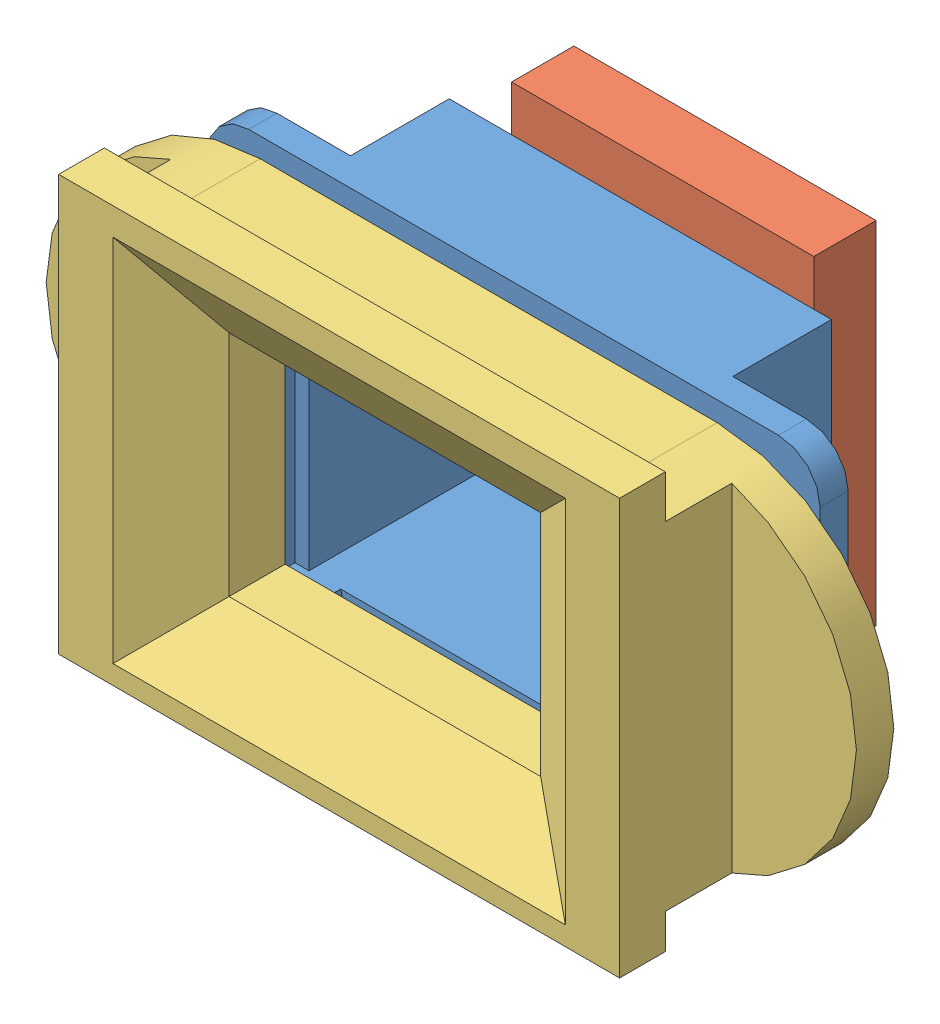
SolidWorks assembly okular, configuration По умолчанию. Lengths in mm.
Overall size (39 20 18.3).
3 component instances, 3 part files, 6 mates.
Components (placement in the parent):
- lensHolder-1: lensHolder [По умолчанию] at origin size (29.5 16.75 9.4)
- display-1: display [По умолчанию] at (0.075 0.225 -5.75) size (14.55 16.9 4)
- cover-1: cover [По умолчанию] at (-0.2 -0.075 7.35) x (1 0 0) z (0 0 -1) size (39 20 7.2)
Mates (geometry in assembly coordinates):
- Совпадение1: coincident anti-aligned: plane of lensHolder-1 through (0 0 -4.75) normal (0 0 -1); plane of display-1 through (0.075 0.225 -4.75) normal (0 0 1)
- Совпадение3: coincident anti-aligned: plane of lensHolder-1 through (-7.35 6.075 -4.75) normal (0 -1 0); plane of display-1 through (-7.2 6.075 -4.75) normal (0 1 0)
- Совпадение4: coincident anti-aligned: plane of lensHolder-1 through (7.35 -6.075 -4.75) normal (-1 0 0); plane of display-1 through (7.35 -5.625 -4.75) normal (1 0 0)
- Совпадение5: coincident anti-aligned: plane of lensHolder-1 through (0 0 4.65) normal (0 0 1); plane of cover-1 through (-0.2 -0.075 4.65) normal (0 0 -1)
- Совпадение6: coincident anti-aligned: plane of lensHolder-1 through (-9.3 7.425 4.65) normal (0 1 0); plane of cover-1 through (-9.7 7.425 4.65) normal (0 -1 0)
- Совпадение7: coincident anti-aligned: plane of lensHolder-1 through (9.3 -7.425 4.65) normal (1 0 0); plane of cover-1 through (9.3 7.425 4.65) normal (-1 0 0)
